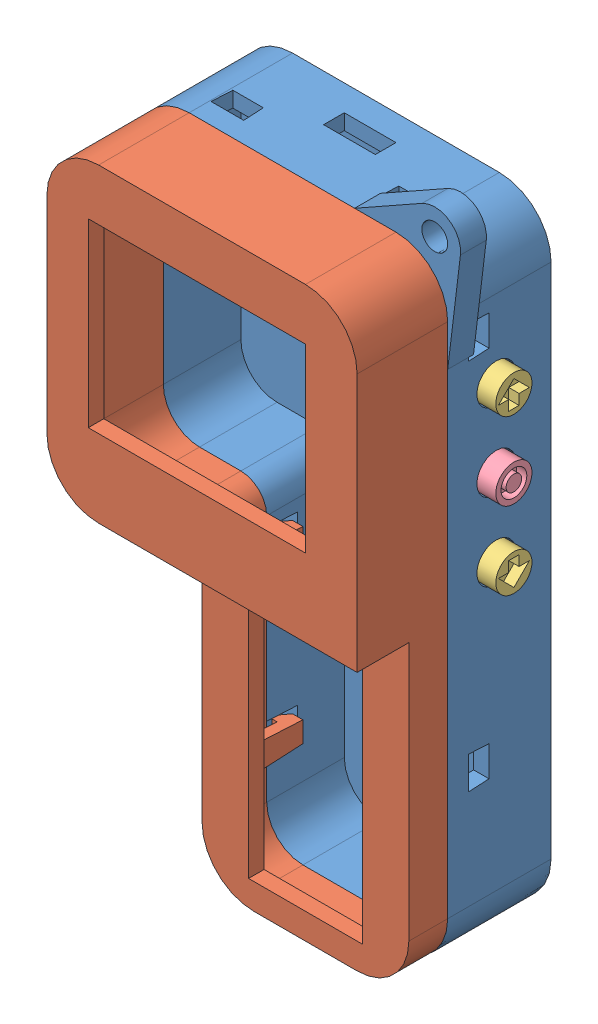
SolidWorks assembly Ensamblaje1, configuration Predeterminado. Lengths in mm.
Overall size (63.42 127.99 37.51).
11 component instances, 10 part files, 28 mates.
Components (placement in the parent):
- Caja_Solido_base-1: Caja_Solido_base [Predeterminado] at (74.0053 -44.9412 -15) size (62.5 127.99 20)
- Caja_SolidoA1-1: Caja_SolidoA1 [Predeterminado] at (74.0053 -44.9412 -17.488) size (60 120 24.51)
- Caja_Solido-1: Caja_Solido [Predeterminado] at (74.0053 -44.9412 -27.488) size (40 60 10) (hidden)
- Pantalla-1: Pantalla [Predeterminado] at (13.3985 -17.6677 18.512) x (1 0 0) z (0 -1 0) size (43 4 45) (hidden)
- sensor-1: sensor [Predeterminado] at (59.6085 -74.8844 -12) x (1 0 0) z (0 -1 0) size (20 30 50) (hidden)
- Arduino-1: Arduino [Predeterminado] at (20.2859 -9.3811 18.512) x (0.008727 0.999962 0) z (-0.999962 0.008727 0) size (33 1 18) (hidden)
- BT-1: BT [Predeterminado] at (1.4235 -23.495 16.512) x (-0.008727 -0.999962 0) z (-0.999962 0.008727 0) size (33 1 18) (hidden)
- Boton_ARROW-1: Boton_ARROW [Predeterminado] at (40.822 -19.746 -9.1387) x (0 0 -1) z (1 0 0) size (12 11.83 9)
- Boton_ARROW-2: Boton_ARROW [Predeterminado] at (40.822 -41.7893 0.3695) x (0 0 1) z (1 0 0) size (12 11.83 9)
- Boton_Sel-1: Boton_Sel [Predeterminado] at (40.822 -34.746 -9.1387) x (0 0 -1) z (1 0 0) size (12 11.83 9)
- babat-1: babat [Predeterminado] at (15.7155 -34.5947 -4.5) x (-1 0 0) z (0 0 -1) size (45 30 15) (hidden)
Mates (geometry in assembly coordinates):
- Coincidente1: coincident aligned: plane of Caja_Solido_base-1 through (43.3985 -0.7677 35) normal (1 0 0); plane of Caja_SolidoA1-1 through (43.3985 -0.7677 22.512) normal (1 0 0)
- Coincidente3: coincident aligned: plane of Caja_Solido_base-1 through (74.0053 -110.7677 -15) normal (0 -1 0); plane of Caja_SolidoA1-1 through (74.0053 -110.7677 -17.488) normal (0 -1 0)
- Paralelo1: parallel anti-aligned: plane of Caja_SolidoA1-1 through (74.0053 -9.5366 12.512) normal (0 0 1); plane of Caja_Solido-1 through (-30.6015 -110.7677 12.512) normal (0 0 -1)
- Coincidente6: coincident aligned: plane of Caja_SolidoA1-1 through (74.0053 -110.7677 -17.488) normal (0 -1 0); plane of Caja_Solido-1 through (74.0053 -110.7677 -27.488) normal (0 -1 0)
- Coincidente7: coincident aligned: plane of Caja_SolidoA1-1 through (43.3985 -0.7677 22.512) normal (1 0 0); plane of Caja_Solido-1 through (43.3985 -0.7677 22.512) normal (1 0 0)
- Coincidente8: coincident anti-aligned: plane of Caja_SolidoA1-1 through (74.0053 -9.5366 12.512) normal (0 0 1); plane of Caja_Solido-1 through (-30.6015 -110.7677 12.512) normal (0 0 -1)
- Coincidente11: coincident anti-aligned: plane of Caja_SolidoA1-1 through (-8.6015 -0.7677 -51.488) normal (0 -1 0); plane of Pantalla-1 through (-6.6015 -0.7677 22.512) normal (0 1 0)
- Coincidente12: coincident anti-aligned: plane of Caja_SolidoA1-1 through (33.3985 -0.7677 -51.488) normal (-1 0 0); plane of Pantalla-1 through (33.3985 -34.7677 22.512) normal (1 0 0)
- Coincidente23: coincident anti-aligned: plane of Caja_SolidoA1-1 through (-6.6015 -0.7677 19.512) normal (0 0 -1); plane of Pantalla-1 through (13.3985 -17.6677 19.512) normal (0 0 1)
- Coincidente24: coincident anti-aligned: plane of Caja_SolidoA1-1 through (12.3985 -53.7677 -61.488) normal (1 0 0); plane of sensor-1 through (12.3985 -55.7677 18) normal (-1 0 0)
- Coincidente25: coincident anti-aligned: plane of Caja_SolidoA1-1 through (12.3985 -105.7677 -61.488) normal (0 1 0); plane of sensor-1 through (12.3985 -105.7677 18) normal (0 -1 0)
- Coincidente26: coincident anti-aligned: plane of Caja_Solido_base-1 through (-6.6015 -0.7677 -12) normal (0 0 1); plane of sensor-1 through (59.6085 -74.8844 -12) normal (0 0 -1)
- Paralelo2: parallel aligned: plane of Caja_SolidoA1-1 through (-6.6015 -0.7677 22.512) normal (0 0 1); plane of Boton_ARROW-1 through (37.822 -11.7677 -5.3846) normal (0 0 1)
- Paralelo3: parallel aligned: plane of Caja_SolidoA1-1 through (43.3985 -0.7677 22.512) normal (1 0 0); plane of Boton_ARROW-1 through (46.822 -15.7677 -4.3846) normal (1 0 0)
- Paralelo5: parallel anti-aligned: plane of Caja_SolidoA1-1 through (-6.6015 9.2323 22.512) normal (0 1 0); plane of Boton_ARROW-2 through (37.822 -49.7677 -5.3846) normal (0 -1 0)
- Coincidente35: coincident aligned: plane of Boton_ARROW-1 through (46.822 -15.7677 -4.3846) normal (1 0 0); plane of Boton_ARROW-2 through (46.822 -45.7677 -4.3846) normal (1 0 0)
- Paralelo6: parallel aligned: plane of Caja_SolidoA1-1 through (-6.6015 -0.7677 22.512) normal (0 0 1); plane of Boton_Sel-1 through (37.822 -26.7677 -5.3846) normal (0 0 1)
- Coincidente37: coincident aligned: plane of Boton_ARROW-1 through (46.822 -15.7677 -4.3846) normal (1 0 0); plane of Boton_Sel-1 through (46.822 -30.7677 -4.3846) normal (1 0 0)
- Concéntrica4: concentric anti-aligned: circle of Caja_Solido_base-1; cylinder of Boton_ARROW-1 through (46.822 -15.7677 -4.3846) axis (-1 0 0) radius 3.5
- Concéntrica6: concentric anti-aligned: cylinder of Caja_Solido_base-1 through (-16.6025 -30.7677 -4.3846) axis (1 0 0) radius 3.75; cylinder of Boton_Sel-1 through (46.822 -30.7677 -4.3846) axis (-1 0 0) radius 3.5
- Concéntrica8: concentric anti-aligned: cylinder of Caja_Solido_base-1 through (-16.6025 -45.7677 -4.3846) axis (1 0 0) radius 3.75; cylinder of Boton_ARROW-2 through (46.822 -45.7677 -4.3846) axis (-1 0 0) radius 3.5
- Coincidente39: coincident anti-aligned: plane of Caja_Solido_base-1 through (-32.6015 -100.7677 5) normal (0 0 1); plane of Caja_SolidoA1-1 through (74.0053 9.2323 5) normal (0 0 -1)
- Tangente1: tangent: plane of Caja_Solido_base-1 through (-6.6015 -0.7677 -12) normal (0 0 1); circle of ?
- Paralelo7: parallel anti-aligned: plane of Caja_Solido_base-1 through (-13.6015 -0.7677 35) normal (1 0 0); plane of ? through (-9.0123 -5.3345 0.4706) normal (-1 0 0)
- Tangente2: tangent: plane of Caja_Solido_base-1 through (-6.6015 6.2323 35) normal (0 -1 0); circle of ?
- Coincidente45: coincident anti-aligned: plane of Caja_Solido_base-1 through (-6.6015 -0.7677 -12) normal (0 0 1); plane of babat-1 through (38.2155 -4.5947 -12) normal (0 0 -1)
- Coincidente48: coincident anti-aligned: plane of Pantalla-1 through (13.3985 -17.6677 18.512) normal (0 0 -1); plane of Arduino-1 through (20.2859 -9.3811 18.512) normal (0 0 1)
- Coincidente49: coincident anti-aligned: plane of Arduino-1 through (20.2859 -9.3811 17.512) normal (0 0 -1); plane of BT-1 through (1.4235 -23.495 17.512) normal (0 0 1)
